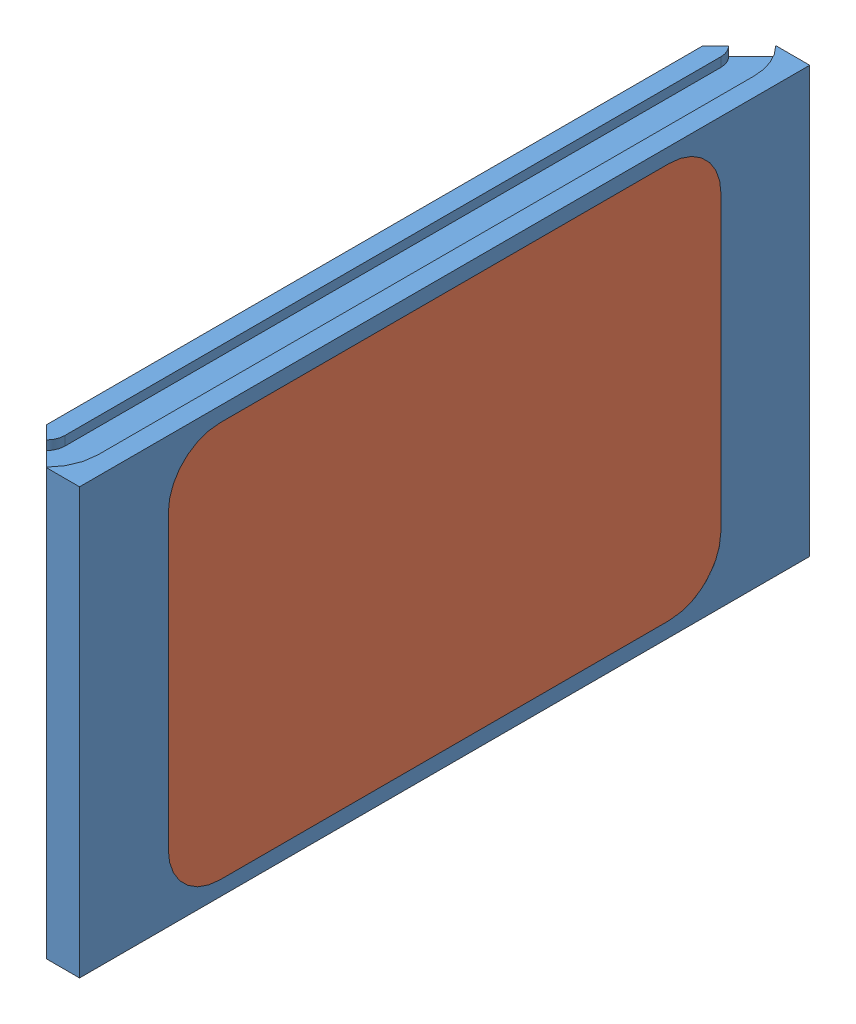
SolidWorks assembly front_plate_assembly, configuration Default. Lengths in mm.
Overall size (19 111 197.4).
2 component instances, 2 part files, 4 mates.
Components (placement in the parent):
- front_plate-1: front_plate [Default] at (260.35 0 0) x (0 0 -1) z (1 0 0) size (197.4 85.21 16)
- front_window_single-1: front_window_single [Default] at (263.35 0 0) x (0 0 -1) z (1 0 0) size (78 111 6)
Mates (geometry in assembly coordinates):
- InPlace1: in place: plane of front_plate-1 through (263.35 -39.5 60.7) normal (1 0 0); plane of front_window_single-1 through (263.35 0 0) normal (1 0 0); moOrthogonalPlaneRef_w of front_plate-1 through (263.35 -39.5 60.7) normal (1 0 0); plane of front_window_single-1 through (263.35 0 0) normal (0 1 0); plane of front_plate-1 through (263.35 -39.5 60.7) normal (1 0 0); plane of front_window_single-1 through (263.35 0 0) normal (0 0 -1); plane of front_plate-1 through (263.35 -41.5 25) normal (1 0 0); unknown of front_window_single-1
- Coincident1: coincident aligned: plane of front_plate-1; plane of front_window_single-1
- Coincident2: coincident aligned: moOrthogonalPlaneRef_w of front_plate-1 through (263.35 0 0) normal (0 1 0); plane of front_window_single-1 through (263.35 0 0) normal (0 1 0)
- Coincident3: coincident anti-aligned: moOrthogonalPlaneRef_w of front_plate-1 through (263.35 0 0) normal (0 0 1); plane of front_window_single-1 through (263.35 0 0) normal (0 0 -1)
